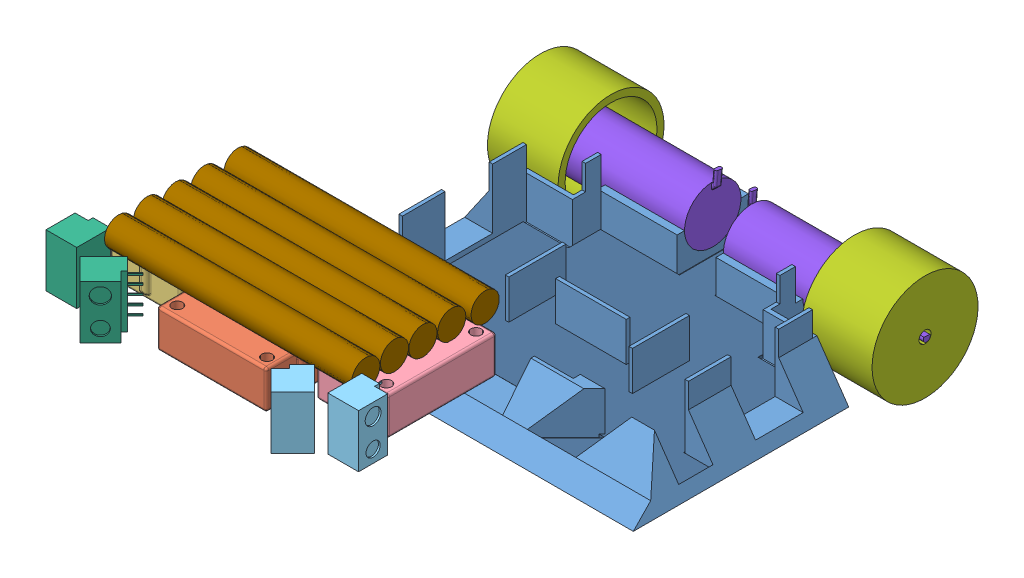
SolidWorks assembly sensorlu1, configuration Varsayılan. Lengths in mm.
Overall size (110.2 70.57 173.37).
18 component instances, 10 part files, 4 mates.
Components (placement in the parent):
- maxon1-1: maxon1 [Varsayılan] at (-30.734 -80.4583 -99.0877) size (100 20 88.1)
- omron4-1: omron4 [Default] at (-25.3066 -38.4453 19.9186) x (-1 0 0) z (0 0 -1) size (37.72 10.8 25.16)
- omron4 - Copy-1: omron4 - Copy [Default] at (-54.8536 -38.2416 3.6404) x (0 0 -1) z (1 0 0) size (37.72 10.8 25.16)
- omron5-1: omron5 [Default] at (3.9353 -27.4961 3.9728) x (0 0 -1) z (-1 0 0) size (37.72 10.8 25.16)
- sharp - Copy-1: sharp - Copy [Default] at (-12.8813 -29.4599 25.5292) x (-0.707107 0 -0.707107) z (0 -1 0) size (12.7 8.7 15)
- sharp - Copy - Copy-1: sharp - Copy - Copy [Default] at (-38.1162 -30.7347 25.6327) x (0.707107 0 -0.707107) z (0 1 0) size (12.7 8.7 15)
- sharp - Copy-2: sharp - Copy [Default] at (18.507 -30.8297 11.7511) x (0 0 -1) z (0 1 0) size (12.7 8.7 15)
- sharp - Copy - Copy-2: sharp - Copy - Copy [Default] at (-69.9574 -29.2337 11.7924) x (0 0 -1) z (0 -1 0) size (12.7 8.7 15)
- tekerlek-1: tekerlek [Default] at (-55.1372 -69.4583 -113.0283) x (-1 0 0) z (0 0.474195 0.88042) size (20 30 30)
- tekerlek-2: tekerlek [Default] at (13.776 -69.4583 -113.0283) x (1 0 0) z (0 -0.022697 0.999742) size (20 30 30)
- maxon-1: maxon [Varsayılan] at (-67.933 -69.4583 -113.0283) x (0 -0.09274 -0.99569) z (1 0 0) size (16 19 50.6)
- maxon-2: maxon [Varsayılan] at (26.267 -69.4583 -113.0283) x (0 0.086209 0.996277) z (-1 0 0) size (16 19 50.6)
- batt4-1: batt4 [Varsayılan] at (-60.6787 -23.7812 20.8722) x (0 0 -1) z (1 0 0) size (8 8 70)
- batt4-2: batt4 [Varsayılan] at (-60.5516 -23.2102 12.8708) x (0 0 -1) z (1 0 0) size (8 8 70)
- batt4-3: batt4 [Varsayılan] at (-60.3912 -23.4835 4.9789) x (0 0 -1) z (1 0 0) size (8 8 70)
- batt4-4: batt4 [Varsayılan] at (-59.7528 -23.373 -11.9894) x (0 0 -1) z (1 0 0) size (8 8 70)
- batt4-5: batt4 [Varsayılan] at (-60.4953 -23.6372 -3.2706) x (0 0 -1) z (1 0 0) size (8 8 70)
- alt kart-1: alt kart [Varsayılan] at (-40.1465 -79.5426 -102.5327) size (94.93 1 85.81)
Mates (geometry in assembly coordinates):
- Concentric3: concentric aligned: circle of tekerlek-2; circle of maxon-2
- Concentric5: concentric aligned: circle of tekerlek-1; circle of maxon-1
- Coincident1: coincident anti-aligned: circle of maxon1-1; circle of maxon-1
- Coincident2: coincident anti-aligned: circle of maxon1-1; circle of maxon-2
